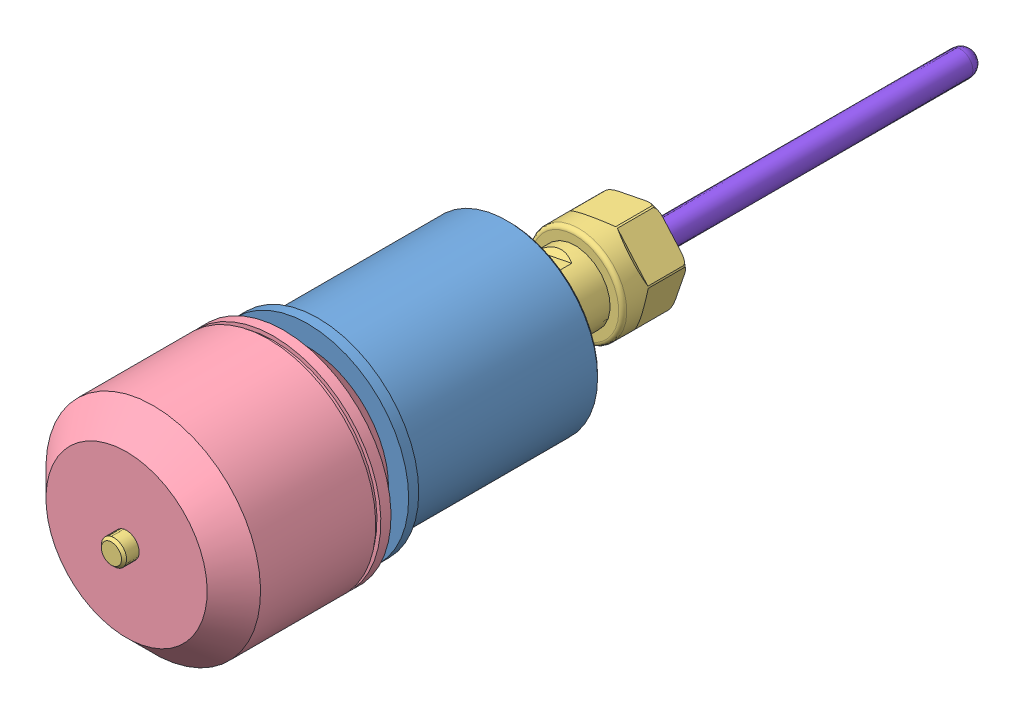
SolidWorks assembly Spindle Motor, configuration Défaut. Lengths in mm.
Overall size (42.6 42.6 171).
9 component instances, 8 part files, 24 mates.
Components (placement in the parent):
- Spindle Bearing Housing-1: Spindle Bearing Housing [Défaut] at (0 0 -33.5) size (40 40 40)
- Bearing Spacer-1: Bearing Spacer [Défaut] at (0 0 -22.5) x (0.17803 -0.984025 0) z (0 0 1) size (12 12 20)
- Shank Collet Chuck-1: Shank Collet Chuck [Défaut] at (0 0 45.5) x (0.194207 -0.980961 0) z (0 0 -1) size (19 19.41 105.21)
- Brushless Motor-1: Brushless Motor [Défaut] at (0 0 6.5) x (1 0 0) z (0 -1 0) size (42.6 36 42.6)
- Top Spacer-1: Top Spacer [Défaut] at (0 0 3.5) size (12 12 4)
- Ball Bearing 607-1: Ball Bearing 607 [Défaut] at (0 0 -2.5) x (0 0 1) z (-1 0 0) size (6 19 19)
- Ball Bearing 607-2: Ball Bearing 607 [Défaut] at (0 0 -28.5) x (0 0 1) z (-0.997808 -0.066178 0) size (6 19 19)
- Housing Spacer-1: Housing Spacer [Défaut] at (0 0 3.5) x (0.06441 0.997924 0) z (0 0 1) size (19 19 3)
- Ball Nose End Mill-2: Ball Nose End Mill [Défaut] at (0 0 -125.5) x (-0.024388 0.999703 0) z (0.999703 0.024388 0) size (5.1 80 5.1)
Mates (geometry in assembly coordinates):
- Coaxiale4: concentric anti-aligned: cylinder of Bearing Spacer-1 through (0 0 -2.5) axis (0 0 -1) radius 6; cylinder of Shank Collet Chuck-1 through (0 0 -34.5) axis (0 0 1) radius 4
- Concentric1: concentric anti-aligned: cylinder of Shank Collet Chuck-1 through (0 0 -34.5) axis (0 0 1) radius 4; cylinder of Brushless Motor-1 through (0 0 6.5) axis (0 0 -1) radius 2.5
- Coincident6: coincident: plane of ? through (83.3313 -30.816 57.0781) normal (0 0 -1); plane of ? through (83.3313 -40.416 57.0781) normal (0 0 1)
- Concentric4: concentric anti-aligned: cylinder of Shank Collet Chuck-1 through (0 0 -34.5) axis (0 0 1) radius 4; cylinder of Top Spacer-1 through (0 0 7.5) axis (0 0 -1) radius 4
- Coincident7: coincident anti-aligned: plane of Brushless Motor-1 through (2.5 0 7.5) normal (0 0 -1); plane of Top Spacer-1 through (0 0 7.5) normal (0 0 1)
- Coincident8: coincident: plane of ? through (83.3313 -30.816 106.0781) normal (0 0 1); plane of Top Spacer-1 through (0 0 3.5) normal (0 0 -1)
- Concentric7: concentric aligned: cylinder of Brushless Motor-1 through (0 0 6.5) axis (0 0 -1) radius 21.3; cylinder of ? through (83.3313 -40.416 85.0781) axis (0 0 -1) radius 21
- Coincident10: coincident anti-aligned: plane of Brushless Motor-1 through (8 0 6.5) normal (0 0 -1); plane of ? through (75.9415 -43.4804 113.0781) normal (0 0 1)
- Concentric8: concentric anti-aligned: cylinder of Shank Collet Chuck-1 through (0 0 -49.916) axis (0 0 1) radius 3.5; cylinder of Ball Bearing 607-2 through (0 0 -28.5) axis (0 0 -1) radius 3.5
- Concentric9: concentric anti-aligned: cylinder of Shank Collet Chuck-1 through (0 0 -49.916) axis (0 0 1) radius 3.5; cylinder of Ball Bearing 607-1 through (0 0 -2.5) axis (0 0 -1) radius 3.5
- Coincident11: coincident anti-aligned: plane of Top Spacer-1 through (0 0 3.5) normal (0 0 -1); plane of Ball Bearing 607-1 through (0 3.8 3.5) normal (0 0 1)
- Coincident12: coincident anti-aligned: plane of Shank Collet Chuck-1 through (0 0 -28.5) normal (0 0 1); plane of Ball Bearing 607-2 through (-0.2515 3.7917 -28.5) normal (0 0 -1)
- Concentric10: concentric aligned: cylinder of Shank Collet Chuck-1 through (0 0 -49.916) axis (0 0 1) radius 3.5; cylinder of Spindle Bearing Housing-1 through (0 0 -60.3701) axis (0 0 1) radius 9.5
- Coincident13: coincident anti-aligned: plane of Spindle Bearing Housing-1 through (0 0 -28.5) normal (0 0 1); plane of Ball Bearing 607-2 through (-0.546 8.2319 -28.5) normal (0 0 -1)
- Coincident14: coincident anti-aligned: plane of Brushless Motor-1 through (8 0 6.5) normal (0 0 -1); plane of Spindle Bearing Housing-1 through (0 0 6.5) normal (0 0 1)
- Concentric11: concentric aligned: circle of Brushless Motor-1; cylinder of Spindle Bearing Housing-1 through (8.8388 -8.8388 -33.5) axis (0 0 -1) radius 3.25
- Coincident15: coincident anti-aligned: plane of Bearing Spacer-1 through (0 0 -22.5) normal (0 0 -1); plane of Ball Bearing 607-2 through (-0.2515 3.7917 -22.5) normal (0 0 1)
- Concentric12: concentric aligned: cylinder of Spindle Bearing Housing-1 through (0 0 6.5) axis (0 0 -1) radius 18; cylinder of Housing Spacer-1 through (0 0 6.5) axis (0 0 -1) radius 9.5
- Coincident16: coincident anti-aligned: plane of Brushless Motor-1 through (8 0 6.5) normal (0 0 -1); plane of Housing Spacer-1 through (0 0 6.5) normal (0 0 1)
- Concentric14: concentric aligned: cylinder of Shank Collet Chuck-1 through (0 0 -47.5) axis (0 0 -1) radius 2.6; cylinder of Ball Nose End Mill-2 through (0 0 -125.5) axis (0 0 -1) radius 2.55
- Distance1: distance = 130 mm anti-aligned: plane of Spindle Bearing Housing-1 through (0 0 4.5) normal (0 0 -1); plane of Ball Nose End Mill-2 through (0 0 -125.5) normal (0 0 1)
- Distance2: distance = 4.5 mm anti-aligned: plane of Spindle Bearing Housing-1 through (0 0 4.5) normal (0 0 -1); plane of assembly through (0 0 0) normal (0 0 1)
- Coïncidente3: coincident aligned: plane of Spindle Bearing Housing-1 through (0 0 -33.5) normal (1 0 0); plane of assembly through (0 0 0) normal (1 0 0)
- Coïncidente4: coincident aligned: plane of Spindle Bearing Housing-1 through (0 0 -33.5) normal (0 1 0); plane of assembly through (0 0 0) normal (0 1 0)
